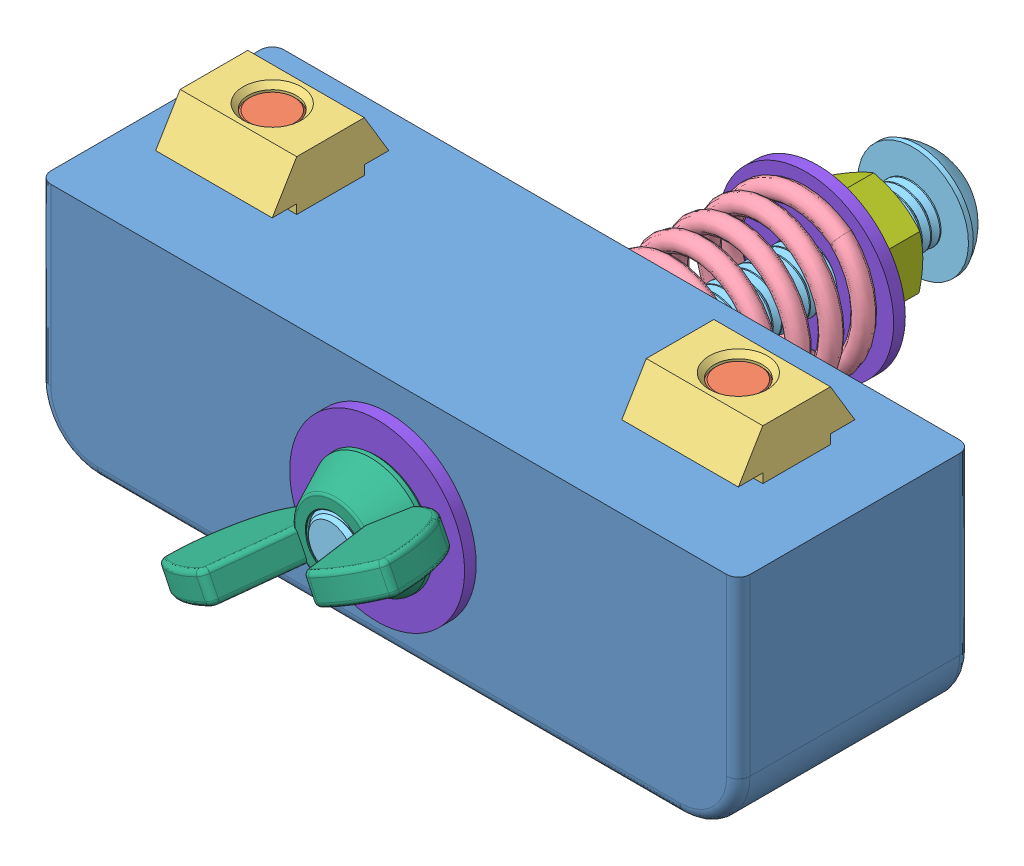
SolidWorks assembly Bed_Leveling_Mount, configuration Default. Lengths in mm.
Overall size (60 28.42 59.39).
11 component instances, 8 part files, 22 mates.
Components (placement in the parent):
- Bed_Leveling_Mount-1: Bed_Leveling_Mount [Default] at origin size (60 20 20)
- 5mmX25mm_Buttonhead(McMaster_92095A216)-3: 5mmX25mm_Buttonhead(McMaster_92095A216) [91239A232] at (20 -22.75 10) x (-0.079632 0 0.996824) z (0 -1 0) size (9.5 9.5 28.3)
- 5mmX25mm_Buttonhead(McMaster_92095A216)-2: 5mmX25mm_Buttonhead(McMaster_92095A216) [91239A232] at (-20 -22.75 10) x (0.273532 0 0.961863) z (0 -1 0) size (9.5 9.5 28.3)
- HNTTSN5-5-1: HNTTSN5-5 [Default] at (20 1.2 10) x (0 -1 0) z (-1 0 0) size (4.3 10 10)
- HNTTSN5-5-2: HNTTSN5-5 [Default] at (-20 1.2 10) x (0 -1 0) z (-1 0 0) size (4.3 10 10)
- 1L_.5OD_.062Wire(McMaster_9657K313)-1: 1L_.5OD_.062Wire(McMaster_9657K313) [Default] at (0 -10 2.8956) x (0.991254 0.131967 0) z (-0.131967 0.991254 0) size (14.01 21.35 14.01)
- 5mmX50mm_Buttonhead(McMaster_92095A483)-2: 5mmX50mm_Buttonhead(McMaster_92095A483) [92095A483] at (0 -10 -27.75) x (-0.999667 0.025809 0) z (0 0 -1) size (9.5 9.5 53.45)
- 5mm_Wingnut(McMaster_94545A225)-1: 5mm_Wingnut(McMaster_94545A225) [94545A225] at (0 -10 21) x (-0.897394 -0.441231 0) z (0 0 -1) size (21.75 10 10.78)
- 5mm_Hex_NyLockNut(McMaster_94205A240)-1: 5mm_Hex_NyLockNut(McMaster_94205A240) [94205A240] at (0 -10 -21.825) x (0.999869 -0.016207 0) z (-0.016207 -0.999869 0) size (8 5.15 9.24)
- M5_Oversized_FlatWasher(McMaster_91100A140)-1: M5_Oversized_FlatWasher(McMaster_91100A140) [91100A140] at (0 -10 -15.825) size (15 15 1)
- M5_Oversized_FlatWasher(McMaster_91100A140)-2: M5_Oversized_FlatWasher(McMaster_91100A140) [91100A140] at (0 -10 21) x (0.986978 -0.160858 0) z (0 0 1) size (15 15 1)
Mates (geometry in assembly coordinates):
- Concentric11: concentric anti-aligned: cylinder of Bed_Leveling_Mount-1 through (20 -27.3539 10) axis (0 1 0) radius 2.6; cylinder of 5mmX25mm_Buttonhead(McMaster_92095A216)-3 through (20 -22.75 10) axis (0 -1 0) radius 4.75
- Coincident11: coincident anti-aligned: plane of Bed_Leveling_Mount-1 through (-25 -20 20) normal (0 -1 0); plane of 5mmX25mm_Buttonhead(McMaster_92095A216)-3 through (24.7349 -20 10.3783) normal (0 1 0)
- Concentric21: concentric anti-aligned: cylinder of Bed_Leveling_Mount-1 through (-20 -27.3539 10) axis (0 1 0) radius 2.6; cylinder of 5mmX25mm_Buttonhead(McMaster_92095A216)-2 through (-20 -22.75 10) axis (0 -1 0) radius 4.75
- Coincident21: coincident anti-aligned: plane of Bed_Leveling_Mount-1 through (-25 -20 20) normal (0 -1 0); plane of 5mmX25mm_Buttonhead(McMaster_92095A216)-2 through (-15.4312 -20 8.7007) normal (0 1 0)
- Concentric3: concentric anti-aligned: cylinder of 5mmX25mm_Buttonhead(McMaster_92095A216)-3 through (20 -22.75 10) axis (0 -1 0) radius 4.75; cylinder of HNTTSN5-5-1 through (20 1.2 10) axis (0 1 0) radius 2.067
- Parallel1: parallel anti-aligned: plane of Bed_Leveling_Mount-1 through (30 0 20) normal (1 0 0); plane of HNTTSN5-5-1 through (15 1.2 10) normal (-1 0 0)
- Distance1: distance = 2 mm anti-aligned: plane of HNTTSN5-5-1 through (15 2 12.9) normal (0 -1 0); plane of Bed_Leveling_Mount-1 through (-30 0 20) normal (0 1 0)
- Concentric4: concentric anti-aligned: cylinder of 5mmX25mm_Buttonhead(McMaster_92095A216)-2 through (-20 -22.75 10) axis (0 -1 0) radius 4.75; cylinder of HNTTSN5-5-2 through (-20 1.2 10) axis (0 1 0) radius 2.067
- Parallel2: parallel anti-aligned: plane of Bed_Leveling_Mount-1 through (30 0 20) normal (1 0 0); plane of HNTTSN5-5-2 through (-25 1.2 10) normal (-1 0 0)
- Distance2: distance = 2 mm anti-aligned: plane of HNTTSN5-5-2 through (-25 2 12.9) normal (0 -1 0); plane of Bed_Leveling_Mount-1 through (-30 0 20) normal (0 1 0)
- Concentric5: concentric anti-aligned: cylinder of Bed_Leveling_Mount-1 through (0 -10 20) axis (0 0 -1) radius 2.6; line of 1L_.5OD_.062Wire(McMaster_9657K313)-1 through (0 -10 -23.8361) axis (0 0 1)
- Coincident7: coincident aligned: plane of Bed_Leveling_Mount-1 through (0 0 3) normal (0 0 -1); plane of 1L_.5OD_.062Wire(McMaster_9657K313)-1
- Concentric22: concentric aligned: cylinder of Bed_Leveling_Mount-1 through (0 -10 20) axis (0 0 -1) radius 2.6; cylinder of 5mmX50mm_Buttonhead(McMaster_92095A483)-2 through (0 -10 -27.75) axis (0 0 -1) radius 4.75
- Distance3: distance = 25 mm anti-aligned: plane of 5mmX50mm_Buttonhead(McMaster_92095A483)-2 through (-0.1226 -14.7484 -25) normal (0 0 1); plane of Bed_Leveling_Mount-1 through (-25 -15 0) normal (0 0 -1)
- Concentric23: concentric aligned: cylinder of Bed_Leveling_Mount-1 through (0 -10 20) axis (0 0 -1) radius 2.6; circle of 5mm_Wingnut(McMaster_94545A225)-1
- Concentric24: concentric aligned: cylinder of 5mmX50mm_Buttonhead(McMaster_92095A483)-2 through (0 -10 -27.75) axis (0 0 -1) radius 4.75; cylinder of 5mm_Hex_NyLockNut(McMaster_94205A240)-1 through (0 -10 -17.5821) axis (0 0 -1) radius 2.1277
- Distance4: distance = 3.175 mm anti-aligned: plane of 5mmX50mm_Buttonhead(McMaster_92095A483)-2 through (-0.1226 -14.7484 -25) normal (0 0 1); plane of 5mm_Hex_NyLockNut(McMaster_94205A240)-1 through (-3.8872 -3.0079 -21.825) normal (0 0 -1)
- Concentric25: concentric anti-aligned: cylinder of 5mmX50mm_Buttonhead(McMaster_92095A483)-2 through (0 -10 -27.75) axis (0 0 -1) radius 4.75; cylinder of M5_Oversized_FlatWasher(McMaster_91100A140)-1 through (0 -10 -16.825) axis (0 0 1) radius 2.65
- Coincident25: coincident anti-aligned: plane of 5mm_Hex_NyLockNut(McMaster_94205A240)-1 through (-3.8872 -3.0079 -16.825) normal (0 0 1); plane of M5_Oversized_FlatWasher(McMaster_91100A140)-1 through (0 -10 -16.825) normal (0 0 -1)
- Concentric26: concentric anti-aligned: cylinder of Bed_Leveling_Mount-1 through (0 -10 20) axis (0 0 -1) radius 2.6; cylinder of M5_Oversized_FlatWasher(McMaster_91100A140)-2 through (0 -10 20) axis (0 0 1) radius 2.65
- Coincident26: coincident anti-aligned: plane of Bed_Leveling_Mount-1 through (-25 -15 20) normal (0 0 1); plane of M5_Oversized_FlatWasher(McMaster_91100A140)-2 through (0 -10 20) normal (0 0 -1)
- Coincident28: coincident anti-aligned: plane of 5mm_Wingnut(McMaster_94545A225)-1 through (0 -10 21) normal (0 0 -1); plane of M5_Oversized_FlatWasher(McMaster_91100A140)-2 through (0 -10 21) normal (0 0 1)
